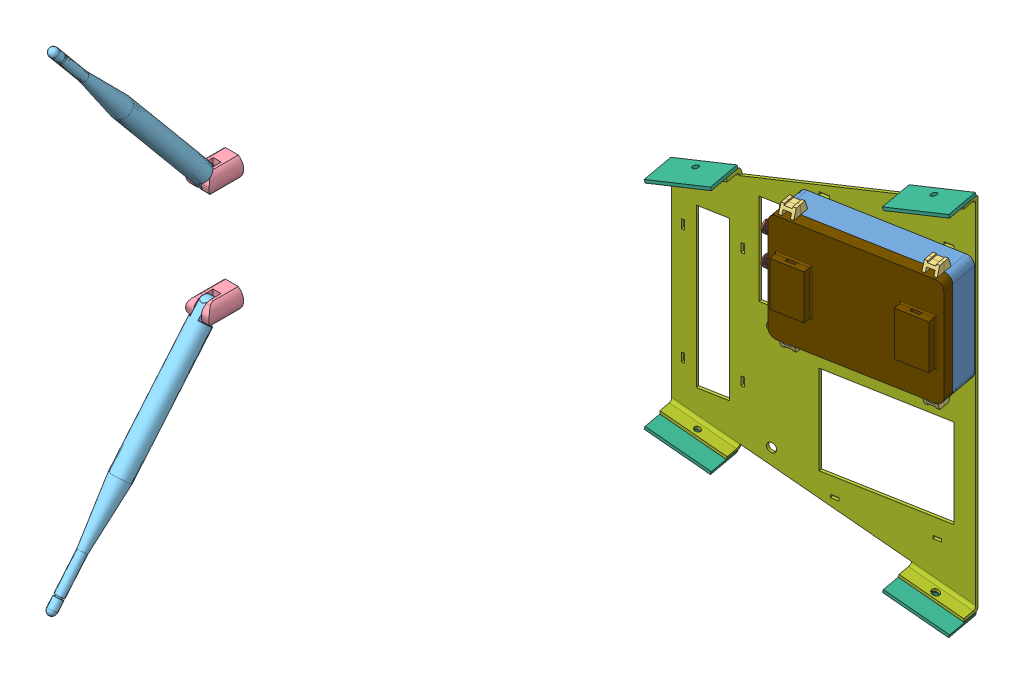
SolidWorks assembly PUTM-G-TM-Assembly, configuration Domyślna. Lengths in mm.
Overall size (370.11 344.19 282.32).
142 component instances, 28 part files, 6 mates.
Components (placement in the parent):
- PUTM-G-TM-Telemetry-Box-1: PUTM-G-TM-Telemetry-Box [Domyślna] at (431.6203 -19.7227 400.2614) x (-0.983943 0 0.178486) z (0.178486 0 0.983943) size (110.5 85 31.5)
  - PUTM-G-TM-obudowa-2: PUTM-G-TM-obudowa [Domyślna] at (16.1836 -69.5929 55.5781) x (-1 0 0) z (0 0 -1) size (103 73 18.5)
  - PUTM-G-TM-PCB-1: PUTM-G-TM-PCB [Domyślna] at (-141.8164 0.9071 62.5781) size (90 60 11.59)
    - TC.step-1: TC.step [Domyślna] at origin size (90 60 11.59)
      - CP_Elec_6.3x7.7.step-1: CP_Elec_6.3x7.7.step [Domyślna] at (126.76 -92.79 1.25) x (-1 0 0) z (0 0 1) size (8.61 8.6 7.7)
        - SOLID.step-1: SOLID.step [Domyślna] at origin size (8.61 8.6 7.7)
      - CP_EIA-3528-21_Kemet-B.step-1: CP_EIA-3528-21_Kemet-B.step [Domyślna] at (159.142 -94.9444 1.25) x (0 -1 0) z (0 0 1) size (3.5 2.8 2.1)
        - SOLID-0.step-1: SOLID-0.step [Domyślna] at origin size (3.5 2.8 2.1)
      - SW_SPST_PTS645.step-1: SW_SPST_PTS645.step [Domyślna] at (158.392 -61.1944 1.25) x (0 -1 0) z (0 0 1) size (9 6 4.3)
        - SOLID-1.step-1: SOLID-1.step [Domyślna] at origin size (9 6 4.3)
      - C_0603_1608Metric.step-1: C_0603_1608Metric.step [Domyślna] at (158.142 -68.1944 1.25) x (-1 0 0) z (0 0 1) size (1.6 0.8 0.8)
        - SOLID-2.step-1: SOLID-2.step [Domyślna] at origin size (1.6 0.8 0.8)
      - PinHeader_1x04_P2.54mm_Vertical.step-1: PinHeader_1x04_P2.54mm_Vertical.step [Domyślna] at (199.392 -86.4444 1.25) x (-1 0 0) z (0 0 1) size (2.54 10.16 11.54)
        - SOLID-3.step-1: SOLID-3.step [Domyślna] at origin size (2.54 10.16 11.54)
      - SOIC-8_3.9x4.9mm_P1.27mm.step-1: SOIC-8_3.9x4.9mm_P1.27mm.step [Domyślna] at (160.892 -62.4444 -0.05) x (-1 0 0) z (0 0 -1) size (6 4.9 1.75)
        - SOLID-4.step-1: SOLID-4.step [Domyślna] at origin size (6 4.9 1.75)
      - TSOT-23.step-1: TSOT-23.step [Domyślna] at (151.892 -62.4444 -0.05) x (-1 0 0) z (0 0 -1) size (2.8 2.9 0.95)
        - SOLID-5.step-1: SOLID-5.step [Domyślna] at origin size (2.8 2.9 0.95)
      - R_1206_3216Metric.step-1: R_1206_3216Metric.step [Domyślna] at (145.892 -62.5444 -0.05) x (0 -1 0) z (0 0 -1) size (3.2 1.6 0.55)
        - SOLID-6.step-1: SOLID-6.step [Domyślna] at origin size (3.2 1.6 0.55)
      - LQFP-144_20x20mm_P0.5mm.step-1: LQFP-144_20x20mm_P0.5mm.step [Domyślna] at (177.642 -73.1944 1.25) size (22 22 1.5)
        - SOLID-7.step-1: SOLID-7.step [Domyślna] at origin size (22 22 1.5)
      - R_1206_3216Metric.step-2: R_1206_3216Metric.step [Domyślna] at (199.642 -64.9444 -0.05) x (-1 0 0) z (0 0 -1) size (3.2 1.6 0.55)
        - SOLID-6.step-1: SOLID-6.step [Domyślna] at origin size (3.2 1.6 0.55)
      - R_1206_3216Metric.step-3: R_1206_3216Metric.step [Domyślna] at (199.642 -67.9444 -0.05) x (-1 0 0) z (0 0 -1) size (3.2 1.6 0.55)
        - SOLID-6.step-1: SOLID-6.step [Domyślna] at origin size (3.2 1.6 0.55)
      - R_1206_3216Metric.step-4: R_1206_3216Metric.step [Domyślna] at (191.392 -56.6944 -0.05) x (-1 0 0) z (0 0 -1) size (3.2 1.6 0.55)
        - SOLID-6.step-1: SOLID-6.step [Domyślna] at origin size (3.2 1.6 0.55)
      - R_1206_3216Metric.step-5: R_1206_3216Metric.step [Domyślna] at (191.392 -47.6944 -0.05) x (-1 0 0) z (0 0 -1) size (3.2 1.6 0.55)
        - SOLID-6.step-1: SOLID-6.step [Domyślna] at origin size (3.2 1.6 0.55)
      - R_1206_3216Metric.step-6: R_1206_3216Metric.step [Domyślna] at (191.392 -50.6944 -0.05) x (-1 0 0) z (0 0 -1) size (3.2 1.6 0.55)
        - SOLID-6.step-1: SOLID-6.step [Domyślna] at origin size (3.2 1.6 0.55)
      - R_1206_3216Metric.step-7: R_1206_3216Metric.step [Domyślna] at (191.392 -53.6944 -0.05) x (-1 0 0) z (0 0 -1) size (3.2 1.6 0.55)
        - SOLID-6.step-1: SOLID-6.step [Domyślna] at origin size (3.2 1.6 0.55)
      - SOT-223.step-1: SOT-223.step [Domyślna] at (136.142 -93.6944 1.25) size (7 6.5 1.7)
        - SOLID-8.step-1: SOLID-8.step [Domyślna] at origin size (7 6.5 1.7)
      - TO-263-5_TabPin3.step-1: TO-263-5_TabPin3.step [Domyślna] at (140.642 -76.6944 1.25) size (15 10 4.42)
        - SOLID-9.step-1: SOLID-9.step [Domyślna] at origin size (15 10 4.42)
      - R_1206_3216Metric.step-8: R_1206_3216Metric.step [Domyślna] at (144.642 -96.1944 1.25) size (3.2 1.6 0.55)
        - SOLID-6.step-1: SOLID-6.step [Domyślna] at origin size (3.2 1.6 0.55)
      - R_1206_3216Metric.step-9: R_1206_3216Metric.step [Domyślna] at (144.642 -91.6944 1.25) x (-1 0 0) z (0 0 1) size (3.2 1.6 0.55)
        - SOLID-6.step-1: SOLID-6.step [Domyślna] at origin size (3.2 1.6 0.55)
      - R_1206_3216Metric.step-10: R_1206_3216Metric.step [Domyślna] at (183.892 -59.6944 -0.05) x (1 0 0) z (0 0 -1) size (3.2 1.6 0.55)
        - SOLID-6.step-1: SOLID-6.step [Domyślna] at origin size (3.2 1.6 0.55)
      - R_1206_3216Metric.step-11: R_1206_3216Metric.step [Domyślna] at (163.142 -85.3444 1.25) x (0 -1 0) z (0 0 1) size (3.2 1.6 0.55)
        - SOLID-6.step-1: SOLID-6.step [Domyślna] at origin size (3.2 1.6 0.55)
      - PinHeader_2x05_P2.54mm_Vertical.step-1: PinHeader_2x05_P2.54mm_Vertical.step [Domyślna] at (173.392 -50.6944 1.25) x (0 -1 0) z (0 0 1) size (5.08 12.7 11.54)
        - SOLID-10.step-1: SOLID-10.step [Domyślna] at origin size (5.08 12.7 11.54)
      - microSD_HC_Hirose_DM3D-SF.step-1: microSD_HC_Hirose_DM3D-SF.step [Domyślna] at (195.892 -52.9444 1.25) x (0 1 0) z (0 0 1)
        - SOLID-11.step-1: SOLID-11.step [Domyślna] at origin
      - D_SMB.step-1: D_SMB.step [Domyślna] at (120.392 -72.4444 1.25) x (-1 0 0) z (0 0 1) size (5.3 3.55 2.15)
        - SOLID-12.step-1: SOLID-12.step [Domyślna] at origin size (5.3 3.55 2.15)
      - LED_1206_3216Metric.step-1: LED_1206_3216Metric.step [Domyślna] at (150.142 -96.1944 1.25) x (-1 0 0) z (0 0 1) size (3.2 1.6 1.1)
        - SOLID-13.step-1: SOLID-13.step [Domyślna] at origin size (3.2 1.6 1.1)
      - LED_1206_3216Metric.step-2: LED_1206_3216Metric.step [Domyślna] at (150.142 -91.6944 1.25) x (-1 0 0) z (0 0 1) size (3.2 1.6 1.1)
        - SOLID-13.step-1: SOLID-13.step [Domyślna] at origin size (3.2 1.6 1.1)
      - D_SMB.step-2: D_SMB.step [Domyślna] at (136.75 -66.75 1.25) x (0 -1 0) z (0 0 1) size (5.3 3.55 2.15)
        - SOLID-12.step-1: SOLID-12.step [Domyślna] at origin size (5.3 3.55 2.15)
      - D_SMB.step-3: D_SMB.step [Domyślna] at (128.142 -63 1.25) x (-1 0 0) z (0 0 1) size (5.3 3.55 2.15)
        - SOLID-12.step-1: SOLID-12.step [Domyślna] at origin size (5.3 3.55 2.15)
      - C_0603_1608Metric.step-2: C_0603_1608Metric.step [Domyślna] at (162.142 -94.9444 1.25) x (0 -1 0) z (0 0 1) size (1.6 0.8 0.8)
        - SOLID-2.step-1: SOLID-2.step [Domyślna] at origin size (1.6 0.8 0.8)
      - C_0603_1608Metric.step-3: C_0603_1608Metric.step [Domyślna] at (191.642 -62.4444 1.25) x (0 1 0) z (0 0 1) size (1.6 0.8 0.8)
        - SOLID-2.step-1: SOLID-2.step [Domyślna] at origin size (1.6 0.8 0.8)
      - CP_Elec_6.3x7.7.step-2: CP_Elec_6.3x7.7.step [Domyślna] at (134.392 -86.1944 1.25) x (-1 0 0) z (0 0 1) size (8.61 8.6 7.7)
        - SOLID.step-1: SOLID.step [Domyślna] at origin size (8.61 8.6 7.7)
      - C_0603_1608Metric.step-4: C_0603_1608Metric.step [Domyślna] at (191.392 -71.4444 1.25) x (0 1 0) z (0 0 1) size (1.6 0.8 0.8)
        - SOLID-2.step-1: SOLID-2.step [Domyślna] at origin size (1.6 0.8 0.8)
      - C_0603_1608Metric.step-5: C_0603_1608Metric.step [Domyślna] at (170.392 -59.4444 1.25) x (-1 0 0) z (0 0 1) size (1.6 0.8 0.8)
        - SOLID-2.step-1: SOLID-2.step [Domyślna] at origin size (1.6 0.8 0.8)
      - C_0603_1608Metric.step-6: C_0603_1608Metric.step [Domyślna] at (152.142 -79.9444 1.25) x (0 1 0) z (0 0 1) size (1.6 0.8 0.8)
        - SOLID-2.step-1: SOLID-2.step [Domyślna] at origin size (1.6 0.8 0.8)
      - C_0603_1608Metric.step-7: C_0603_1608Metric.step [Domyślna] at (152.142 -76.1944 1.25) x (0 1 0) z (0 0 1) size (1.6 0.8 0.8)
        - SOLID-2.step-1: SOLID-2.step [Domyślna] at origin size (1.6 0.8 0.8)
      - C_0603_1608Metric.step-8: C_0603_1608Metric.step [Domyślna] at (180.642 -59.4444 1.25) x (-1 0 0) z (0 0 1) size (1.6 0.8 0.8)
        - SOLID-2.step-1: SOLID-2.step [Domyślna] at origin size (1.6 0.8 0.8)
      - C_0603_1608Metric.step-9: C_0603_1608Metric.step [Domyślna] at (160.892 -66.4444 -0.05) x (1 0 0) z (0 0 -1) size (1.6 0.8 0.8)
        - SOLID-2.step-1: SOLID-2.step [Domyślna] at origin size (1.6 0.8 0.8)
      - C_0603_1608Metric.step-10: C_0603_1608Metric.step [Domyślna] at (169.642 -86.9444 1.25) size (1.6 0.8 0.8)
        - SOLID-2.step-1: SOLID-2.step [Domyślna] at origin size (1.6 0.8 0.8)
      - C_0603_1608Metric.step-11: C_0603_1608Metric.step [Domyślna] at (140.45 -88.95 1.25) x (-1 0 0) z (0 0 1) size (1.6 0.8 0.8)
        - SOLID-2.step-1: SOLID-2.step [Domyślna] at origin size (1.6 0.8 0.8)
      - C_0603_1608Metric.step-12: C_0603_1608Metric.step [Domyślna] at (175.6045 -59.4444 1.25) x (-1 0 0) z (0 0 1) size (1.6 0.8 0.8)
        - SOLID-2.step-1: SOLID-2.step [Domyślna] at origin size (1.6 0.8 0.8)
      - C_0603_1608Metric.step-13: C_0603_1608Metric.step [Domyślna] at (176.142 -86.9444 1.25) size (1.6 0.8 0.8)
        - SOLID-2.step-1: SOLID-2.step [Domyślna] at origin size (1.6 0.8 0.8)
      - CP_Elec_6.3x7.7.step-3: CP_Elec_6.3x7.7.step [Domyślna] at (128.142 -69 1.25) x (-1 0 0) z (0 0 1) size (8.61 8.6 7.7)
        - SOLID.step-1: SOLID.step [Domyślna] at origin size (8.61 8.6 7.7)
      - C_0603_1608Metric.step-14: C_0603_1608Metric.step [Domyślna] at (163.142 -78.4444 1.25) x (0 1 0) z (0 0 1) size (1.6 0.8 0.8)
        - SOLID-2.step-1: SOLID-2.step [Domyślna] at origin size (1.6 0.8 0.8)
      - C_0603_1608Metric.step-15: C_0603_1608Metric.step [Domyślna] at (191.392 -76.4444 1.25) x (0 1 0) z (0 0 1) size (1.6 0.8 0.8)
        - SOLID-2.step-1: SOLID-2.step [Domyślna] at origin size (1.6 0.8 0.8)
      - C_0603_1608Metric.step-16: C_0603_1608Metric.step [Domyślna] at (181.142 -86.9444 1.25) size (1.6 0.8 0.8)
        - SOLID-2.step-1: SOLID-2.step [Domyślna] at origin size (1.6 0.8 0.8)
      - C_1206_3216Metric.step-1: C_1206_3216Metric.step [Domyślna] at (155.642 -90.4444 1.25) x (0 1 0) z (0 0 1) size (3.2 1.6 1.6)
        - SOLID-14.step-1: SOLID-14.step [Domyślna] at origin size (3.2 1.6 1.6)
      - C_0603_1608Metric.step-17: C_0603_1608Metric.step [Domyślna] at (163.892 -72.1944 1.25) x (0 -1 0) z (0 0 1) size (1.6 0.8 0.8)
        - SOLID-2.step-1: SOLID-2.step [Domyślna] at origin size (1.6 0.8 0.8)
      - C_0603_1608Metric.step-18: C_0603_1608Metric.step [Domyślna] at (163.142 -81.4444 1.25) x (0 -1 0) z (0 0 1) size (1.6 0.8 0.8)
        - SOLID-2.step-1: SOLID-2.step [Domyślna] at origin size (1.6 0.8 0.8)
      - R_1206_3216Metric.step-12: R_1206_3216Metric.step [Domyślna] at (165.76 -46.2775 -0.05) x (0 1 0) z (0 0 -1) size (3.2 1.6 0.55)
        - SOLID-6.step-1: SOLID-6.step [Domyślna] at origin size (3.2 1.6 0.55)
      - C_1206_3216Metric.step-2: C_1206_3216Metric.step [Domyślna] at (184.892 -87.4444 1.25) x (0 1 0) z (0 0 1) size (3.2 1.6 1.6)
        - SOLID-14.step-1: SOLID-14.step [Domyślna] at origin size (3.2 1.6 1.6)
      - C_1206_3216Metric.step-3: C_1206_3216Metric.step [Domyślna] at (192.892 -65.1944 1.25) x (-1 0 0) z (0 0 1) size (3.2 1.6 1.6)
        - SOLID-14.step-1: SOLID-14.step [Domyślna] at origin size (3.2 1.6 1.6)
      - COMPOUND.step-1: COMPOUND.step [Domyślna] at origin size (90 60 1.2)
  - PUTM-G-TM-Cover-1: PUTM-G-TM-Cover [Domyślna] at (16.1836 -69.5929 74.0781) size (103 73 13)
  - PUTM-G-TM-mount-3: PUTM-G-TM-mount [Domyślna] at (-24.3164 -44.0929 62.5781) x (0 1 0) z (0 0 -1) size (10 9.77 5)
  - PUTM-G-TM-mount-6: PUTM-G-TM-mount [Domyślna] at (-24.3164 -94.0929 62.5781) x (0 1 0) z (0 0 -1) size (10 9.77 5)
  - PUTM-G-TM-mount-5: PUTM-G-TM-mount [Domyślna] at (38.1836 -44.0929 62.5781) x (0 1 0) z (0 0 -1) size (10 9.77 5)
  - PUTM-G-TM-mount-7: PUTM-G-TM-mount [Domyślna] at (55.6836 -94.0929 62.5781) x (0 -1 0) z (0 0 -1) size (10 9.77 5)
  - PUTM-G-TM-Radio modem RFD 900x-1: PUTM-G-TM-Radio modem RFD 900x [По умолчанию] at (25.1836 -65.0929 73.0781) x (0 -1 0) z (0 0 1) size (31 58.7 12.5)
  - PUTM-G-TM-MocowaniePokrywy-7: PUTM-G-TM-MocowaniePokrywy [Domyślna] at (-21.3164 -106.0929 74.0781) x (-1 0 0) z (0 0 1) size (9 6 5.88)
  - PUTM-G-TM-MocowaniePokrywy-9: PUTM-G-TM-MocowaniePokrywy [Domyślna] at (-30.3164 -106.0929 74.0781) x (1 0 0) z (0 0 -1) size (9 6 5.88)
  - PUTM-G-TM-MocowaniePokrywy-8: PUTM-G-TM-MocowaniePokrywy [Domyślna] at (62.6836 -106.0929 74.0781) x (-1 0 0) z (0 0 1) size (9 6 5.88)
  - PUTM-G-TM-MocowaniePokrywy-10: PUTM-G-TM-MocowaniePokrywy [Domyślna] at (53.6836 -106.0929 74.0781) x (1 0 0) z (0 0 -1) size (9 6 5.88)
  - PUTM-G-TM-MocowaniePokrywy-13: PUTM-G-TM-MocowaniePokrywy [Domyślna] at (53.6836 -33.0929 74.0781) size (9 6 5.88)
  - PUTM-G-TM-MocowaniePokrywy-14: PUTM-G-TM-MocowaniePokrywy [Domyślna] at (62.6836 -33.0929 74.0781) x (-1 0 0) z (0 0 -1) size (9 6 5.88)
  - PUTM-G-TM-MocowaniePokrywy-15: PUTM-G-TM-MocowaniePokrywy [Domyślna] at (-21.3164 -33.0929 74.0781) x (-1 0 0) z (0 0 -1) size (9 6 5.88)
  - PUTM-G-TM-MocowaniePokrywy-16: PUTM-G-TM-MocowaniePokrywy [Domyślna] at (-30.3164 -33.0929 74.0781) size (9 6 5.88)
- PUTM-G-TM-Antenne-Mounting-1: PUTM-G-TM-Antenne-Mounting [Domyślna] at (129.1352 41.0234 617.1578) x (0 0 -1) z (-1 0 0) size (23.52 13.43 16)
- PUTM-G-TM-Antenne-Mounting-2: PUTM-G-TM-Antenne-Mounting [Domyślna] at (113.0818 -39.074 614.6626) x (0 0 -1) z (1 0 0) size (23.52 13.43 16)
- PUTM-G-TM-Antenne-1: PUTM-G-TM-Antenne [Domyślna] at (119.873 -44.2963 619.0847) x (0 -0.764252 0.644918) z (-1 0 0) size (173.5 13 13)
- PUTM-G-TM-Antenne-2: PUTM-G-TM-Antenne [Domyślna] at (122.4264 46.2903 621.5268) x (0 0.768579 0.639755) z (-1 0 0) size (173.5 13 13)
- PUTM-G-MS-Mounting-Mounting-1: PUTM-G-MS-Mounting-Mounting [Domyślna] at (137.3076 -39.9999 -24.9074) size (42.76 13.05 29.17)
- PUTM-G-MS-Mounting-Mounting-2: PUTM-G-MS-Mounting-Mounting [Domyślna] at origin size (42.76 13.05 29.17)
- PUTM-G-MS-Mounting-Mounting-8: PUTM-G-MS-Mounting-Mounting [Domyślna] at (-6.3721 22.5933 1.1559) x (0.852991 0.521244 0.026667) z (0.026667 -0.094553 0.995163) size (42.76 13.05 29.17)
- PUTM-G-MS-Mounting-Mounting-9: PUTM-G-MS-Mounting-Mounting [Domyślna] at (130.9355 62.5931 -23.7515) x (0.852991 0.521244 0.026667) z (0.026667 -0.094553 0.995163) size (42.76 13.05 29.17)
- PUTM-G-MS-Boxes-Mounting-1: PUTM-G-MS-Boxes-Mounting [Domyślna] at (312.4952 0 478.3557) x (0.983943 0 -0.178486) z (-0.178486 0 -0.983943) size (178 245.48 12)
- PUTM-FT-FABORY_ISO912_M4x10-1: PUTM-FT-FABORY_ISO912_M4x10 [M6x35 [07071.060.035]] at (357.8673 -73.7699 461.9947) x (-0.178486 0 -0.983943) z (0.137641 -0.990167 -0.024968) size (41 10 10)
- PUTM-FT-FABORY_ISO912_M4x10-2: PUTM-FT-FABORY_ISO912_M4x10 [M6x35 [07071.060.035]] at (357.8673 -2.7699 461.9947) x (-0.178486 0 -0.983943) z (0.137641 -0.990167 -0.024968) size (41 10 10)
- PUTM-FT-FABORY_DIN985-1: PUTM-FT-FABORY_DIN985 [M6 [12348.060.001]] at (359.5629 -73.7699 471.3422) x (0.983943 0 -0.178486) z (0.178486 0 0.983943) size (11.9 10.35 6.18)
- PUTM-FT-FABORY_DIN985-2: PUTM-FT-FABORY_DIN985 [M6 [12348.060.001]] at (359.5629 -2.7699 471.3422) x (0.983943 0 -0.178486) z (0.178486 0 0.983943) size (11.9 10.35 6.18)
- PUTM-FT-FABORY_ISO912_M4x10-3: PUTM-FT-FABORY_ISO912_M4x10 [M4x30 [07071.040.030]] at (319.6056 -82.8471 483.1638) x (-0.271117 -0.961289 0.04918) z (-0.608477 0.210754 0.765074) size (14 7 7)
- PUTM-FT-FABORY_ISO912_M4x10-4: PUTM-FT-FABORY_ISO912_M4x10 [M4x30 [07071.040.030]] at (456.9132 -122.847 458.2564) x (-0.271117 -0.961289 0.04918) z (-0.608477 0.210754 0.765074) size (14 7 7)
- PUTM-FT-FABORY_DIN985-3: PUTM-FT-FABORY_DIN985 [M4 [12348.040.001]] at (321.7535 -75.2312 482.7741) x (0.700066 -0.161861 0.695491) z (0.271117 0.961289 -0.04918) size (8.48 7.4 5.2)
- PUTM-FT-FABORY_DIN985-4: PUTM-FT-FABORY_DIN985 [M4 [12348.040.001]] at (459.0612 -115.2311 457.8667) x (0.66795 -0.151104 0.728705) z (0.271117 0.961289 -0.04918) size (8.48 7.4 5.2)
- PUTM-FT-FABORY_ISO912_M4x10-5: PUTM-FT-FABORY_ISO912_M4x10 [M4x30 [07071.040.030]] at (319.6056 82.8471 483.1638) x (-0.271117 0.961289 0.04918) z (0.842945 0.261786 -0.470012) size (14 7 7)
- PUTM-FT-FABORY_ISO912_M4x10-6: PUTM-FT-FABORY_ISO912_M4x10 [M4x30 [07071.040.030]] at (456.9132 122.847 458.2564) x (-0.271117 0.961289 0.04918) z (-0.17783 0.000191 -0.984061) size (14 7 7)
- PUTM-FT-FABORY_DIN985-5: PUTM-FT-FABORY_DIN985 [M4 [12348.040.001]] at (321.7535 75.2312 482.7741) x (0.899558 0.234865 0.368284) z (0.271117 -0.961289 -0.04918) size (8.48 7.4 5.2)
- PUTM-FT-FABORY_DIN985-6: PUTM-FT-FABORY_DIN985 [M4 [12348.040.001]] at (459.0612 115.2311 457.8667) x (0.939261 0.275384 -0.204823) z (0.271117 -0.961289 -0.04918) size (8.48 7.4 5.2)
Mates (geometry in assembly coordinates):
- Concentric1: concentric aligned: cylinder of PUTM-G-MS-Mounting-Mounting-9 through (457.9977 119.0018 458.0597) axis (0.271117 -0.961289 -0.04918) radius 2; cylinder of PUTM-G-MS-Boxes-Mounting-1 through (456.35 124.844 458.3585) axis (0.271117 -0.961289 -0.04918) radius 2.5
- Coincident1: coincident anti-aligned: plane of PUTM-G-MS-Mounting-Mounting-9 through (134.3927 50.3352 -24.3786) normal (0.271117 -0.961289 -0.04918); plane of PUTM-G-MS-Boxes-Mounting-1 through (476.5504 122.7419 446.5637) normal (-0.271117 0.961289 0.04918)
- Parallel1: parallel anti-aligned: line of PUTM-G-MS-Mounting-Mounting-9 through (480.7449 124.7705 470.7026) axis (-0.945853 -0.275542 0.171576); line of PUTM-G-MS-Boxes-Mounting-1 through (441.3793 109.8721 465.1395) axis (0.945853 0.275542 -0.171576)
- Concentric2: concentric aligned: cylinder of PUTM-G-MS-Mounting-Mounting-8 through (320.6901 79.002 482.9671) axis (0.271117 -0.961289 -0.04918) radius 2; cylinder of PUTM-G-MS-Boxes-Mounting-1 through (319.0424 84.8441 483.266) axis (0.271117 -0.961289 -0.04918) radius 2
- Coincident2: coincident anti-aligned: plane of PUTM-G-MS-Mounting-Mounting-8 through (-2.9149 10.3353 0.5288) normal (0.271117 -0.961289 -0.04918); plane of PUTM-G-MS-Boxes-Mounting-1 through (476.5504 122.7419 446.5637) normal (-0.271117 0.961289 0.04918)
- Parallel2: parallel aligned: line of PUTM-G-MS-Mounting-Mounting-8 through (343.4373 84.7707 495.61) axis (-0.945853 -0.275542 0.171576); line of PUTM-G-MS-Boxes-Mounting-1 through (341.7484 82.8481 483.2124) axis (-0.945853 -0.275542 0.171576)
